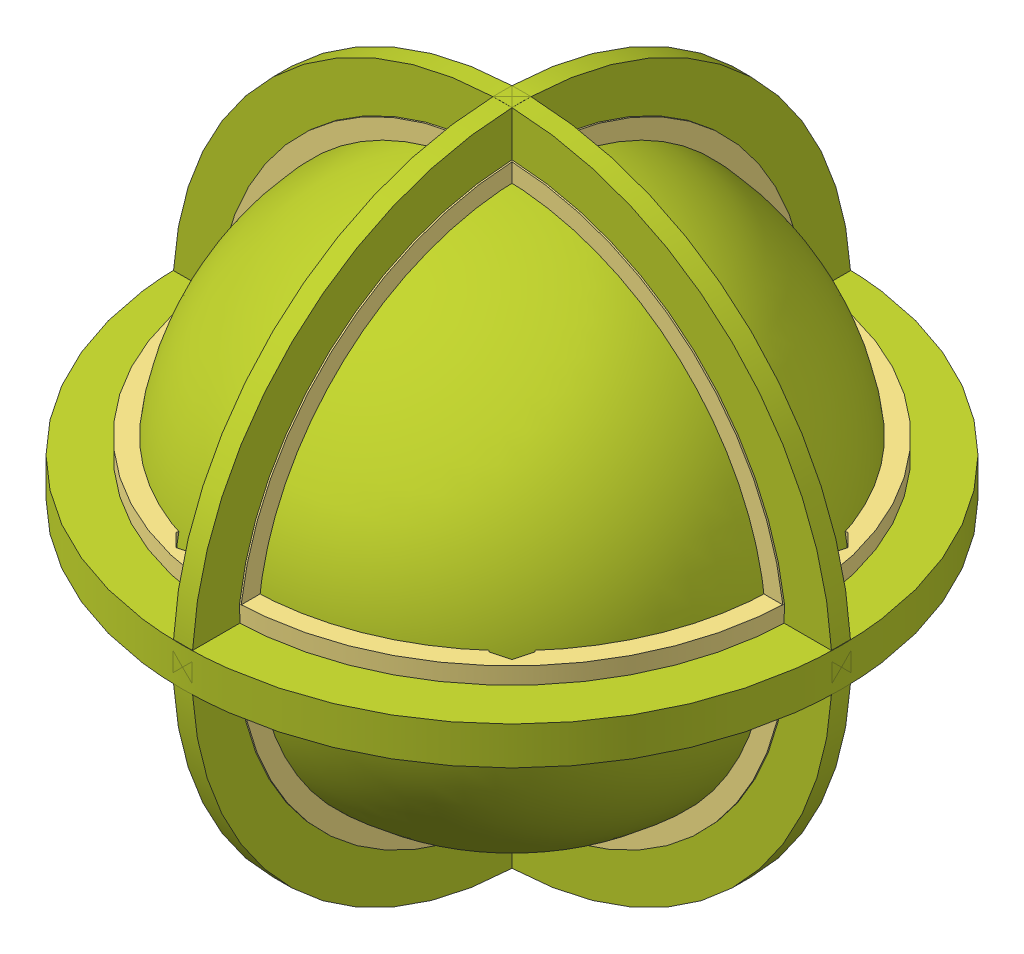
SolidWorks assembly Drifter2_Assem_GSM2, configuration Default. Lengths in mm.
Overall size (104 104 104).
11 component instances, 7 part files, 19 mates.
Components (placement in the parent):
- Sparkfun_NEO-M8P-1: Sparkfun_NEO-M8P [Default] at (27.8484 1.5059 0) x (0 -1 0) z (0 0 1) size (33 4.73 41.24)
- Teensy_3-2-1: Teensy_3-2 [Default] at (19.9056 7.9504 0) x (0 0 -1) z (0 -1 0) size (35.56 4.07 17.78)
- Housing2_Boss-1: Housing2_Boss [2-230 O-ring] at origin size (89 44.86 89) (hidden)
- Housing2_Boss-2: Housing2_Boss [Housing TOP] x (1 0 0) z (0 0 -1) size (89 48.86 89) (hidden)
- EXVIST_4GLTEGSM_EC25-AFX-1: EXVIST_4GLTEGSM_EC25-AFX [USB_desolder] at (-19.7642 4.7661 -22.5005) x (0 0 1) z (0 -1 0) size (49.74 7.08 29.97)
- Battery_AllSizes_configurations-5: Battery_AllSizes_configurations [500mAH] at (0 24.475 -9.8263) x (1 0 0) z (0 1 0) size (31 9 20)
- Battery_AllSizes_configurations-6: Battery_AllSizes_configurations [500mAH] at (0 24.475 9.8263) x (1 0 0) z (0 -1 0) size (31 9 20)
- Battery_AllSizes_configurations-7: Battery_AllSizes_configurations [500mAH] at (0 27.6651 0) x (1 0 0) z (0 1 0) size (31 9 20)
- MA104.C.AB.015_AXIS-1: MA104.C.AB.015_AXIS [Default] at (0 -10.6356 0) x (1 0 0) z (0 -1 0) size (48.81 49.43 49.77)
  - MA104.C.AB.015-1: MA104.C.AB.015 [Default] at (10.5424 -0.5484 -13.2956) size (48.81 49.43 51.31)
- BALL-1: BALL [80mm] at origin size (104 104 104)
Mates (geometry in assembly coordinates):
- Parallel1: parallel aligned: plane of Teensy_3-2-1 through (21.4756 16.8404 17.78) normal (0 0 1)
- Parallel5: parallel anti-aligned: plane of Sparkfun_NEO-M8P-1 through (29.4384 18.0059 -20.62) normal (0 0 -1)
- Angle5: planar angle = 1.570796 rad aligned: plane of Teensy_3-2-1 through (21.4756 -0.9396 17.78) normal (0 -1 0)
- Angle4: planar angle = 1.570796 rad aligned: plane of Sparkfun_NEO-M8P-1 through (29.4384 -14.9941 20.62) normal (0 -1 0)
- Coincident17: coordinate: point of Housing2_Boss-1
- Angle6: planar angle = 1.570796 rad aligned: plane of EXVIST_4GLTEGSM_EC25-AFX-1 through (-19.7642 4.7661 -22.5005) normal (0 -1 0)
- Coincident26: coincident aligned: plane of Battery_AllSizes_configurations-5 through (0 24.475 -9.8263) normal (1 0 0)
- Angle3: planar angle = 1.570796 rad aligned: plane of Battery_AllSizes_configurations-5 through (0 24.475 -9.8263) normal (0 1 0)
- Coincident28: coincident: unknown of Battery_AllSizes_configurations-7
- Coincident29: coincident anti-aligned: plane of Battery_AllSizes_configurations-7 through (0 27.6651 0) normal (0 0 -1)
- Coincident32: coincident aligned: plane of Battery_AllSizes_configurations-7 through (0 27.6651 0) normal (1 0 0)
- Coincident35: coincident: unknown of MA104.C.AB.015_AXIS-1
- Parallel12: parallel anti-aligned: plane of MA104.C.AB.015_AXIS-1 through (0 -10.6356 0) normal (0 -1 0)
- Coincident38: coincident aligned: plane of MA104.C.AB.015_AXIS-1 through (0 -10.6356 0) normal (0 0 1)
- Coincident39: coordinate: unknown of BALL-1
- Coincident40: coincident: unknown of BALL-1
- Coincident41: coincident: unknown of Sparkfun_NEO-M8P-1
- Coincident42: coincident: unknown of Teensy_3-2-1
- Coincident44: coincident anti-aligned: plane of EXVIST_4GLTEGSM_EC25-AFX-1 through (-19.7642 4.7661 0) normal (0 0 -1)
